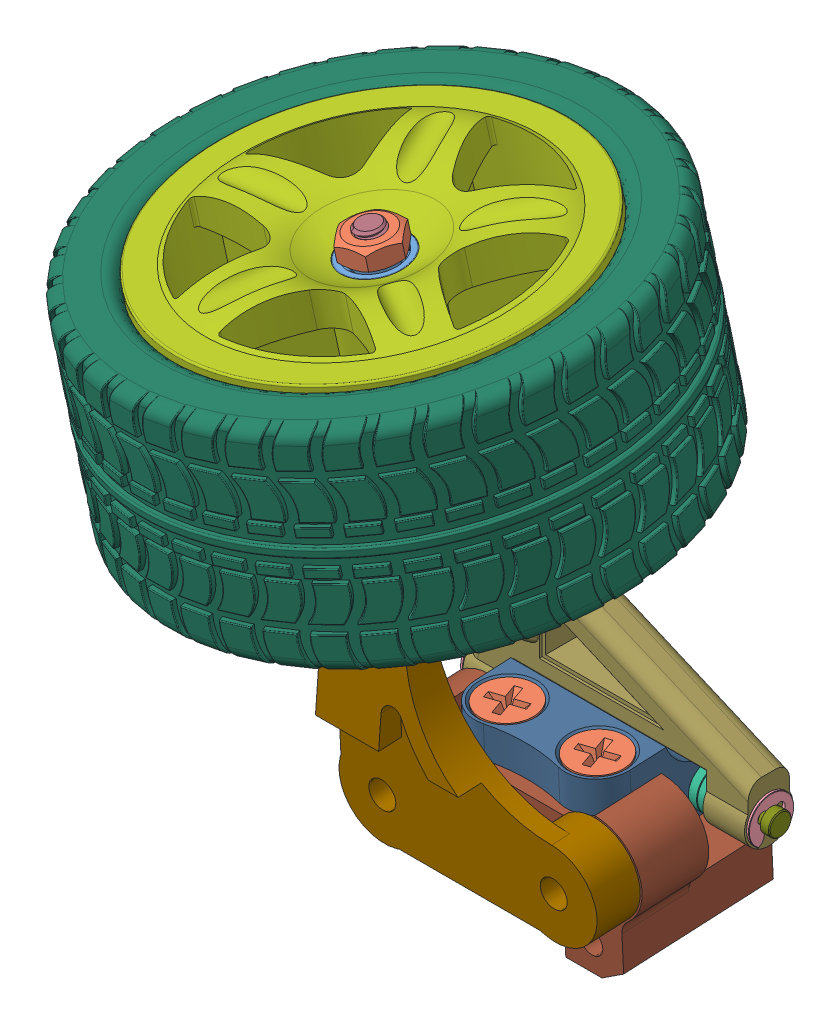
SolidWorks assembly 右前轮, configuration 默认. Lengths in mm.
35 component instances, 21 part files, 72 mates.
Components (placement in the parent):
- 半球型活动头-1: 半球型活动头 [默认] at (-78.9376 -3.6559 -21.7438) x (0.882357 -0.468353 -0.045739) z (-0.470427 -0.875403 -0.111216) size (5.8 4.8 5.8)
- 沉头螺钉-M3-1: 沉头螺钉-M3 [GB_WOOD_SCREWS_TYPE135 3X8-C] at (-71.5787 -28.9343 -13.2981) x (0 -0.998761 -0.049759) z (0.300279 -0.047463 0.95267) size (8.5 6 6)
- 弹簧-1: 弹簧 [默认] at (-76.6558 -7.7661 0.9567) x (0.999717 0.018907 0.014412) z (-0.012048 -0.119649 0.992743) size (4.64 4.5 4.5)
- 挡圈-M2.5-1: 挡圈-M2.5 [默认] at (-50.8787 -34.3142 -21.8764) x (0 0 1) z (-1 0 0) size (5 4.5 0.3)
- 挡圈-M3-1: 挡圈-M3 [默认] at (-76.3474 -4.7031 -24.4576) x (0.999921 0.00221 0.012402) z (-0.012048 -0.119649 0.992743) size (6 5.32 0.3)
- 垫片-M3-1: 垫片-M3 [默认] at (-56.8787 -34.3142 -21.8764) x (0 0.117541 -0.993068) z (-1 0 0) size (4.5 4.5 1)
- 轮毂-前轮-1: 轮毂-前轮 [默认] at (-82.7922 12.0911 -9.4167) x (-0.642369 0.012117 -0.7663) z (-0.756725 -0.168364 0.631681) size (40 26.36 40)
- 前拉杆球头-1: 前拉杆球头 [默认] at (-76.3787 -5.0142 -21.8764) x (0 1 0) z (1 0 0) size (16.5 5.82 9)
- 前轮悬挂固定座-右-1: 前轮悬挂固定座-右 [默认] at (-76.5787 -35.9843 -6.4404) x (1 0 0) z (0 -0.049759 0.998761) size (28.6 39.6 7.36)
- 前轮悬挂连接件上半部分-右-1: 前轮悬挂连接件上半部分-右 [默认] at (-57.9787 -34.3142 -21.8764) x (0 -0.049759 0.998761) z (-1 0 0) size (14.6 8.6 17.2)
- 前轮悬挂连接件下半部分-右-1: 前轮悬挂连接件下半部分-右 [默认] at (-57.5787 -35.845 -9.237) x (0 -0.998761 -0.049759) z (0 0.049759 -0.998761) size (16 29 16.6)
- 前轮悬挂支撑臂-1: 前轮悬挂支撑臂 [默认] at (-76.3787 -34.3142 -24.1764) size (31.32 16.5 6)
- 前轮轴-1: 前轮轴 [默认] at (-80.2678 -8.4104 -11.8569) x (0.428571 0.158643 -0.889471) z (0.121363 -0.98565 -0.117322) size (4.6 4.19 25.74)
- 丝杆-1: 丝杆 [默认] at (-76.3787 -23.5142 -21.8764) x (0.776614 0 -0.629977) z (0 -1 0) size (3.03 3.46 12.09)
- 橡胶胎-1: 橡胶胎 [默认] at (-82.8165 12.2883 -9.3932) x (-0.642369 0.012117 -0.7663) z (-0.756725 -0.168364 0.631681) size (52.2 24.12 52.2)
- 悬挂销钉-M2.5-1: 悬挂销钉-M2.5 [默认] at (-49.8787 -34.3142 -21.8764) x (0 0.773962 0.633232) z (-1 0 0) size (2.5 2.5 34)
- 悬挂销钉-M3-1: 悬挂销钉-M3 [默认] at (-76.3378 -4.6074 -25.2518) x (0.999717 0.018907 0.014412) z (-0.012048 -0.119649 0.992743) size (3 3 27.5)
- 沉头螺钉-M3-2: 沉头螺钉-M3 [GB_WOOD_SCREWS_TYPE135 3X8-C] at (-61.5787 -28.9343 -13.2981) x (0 -0.998761 -0.049759) z (0.300279 -0.047463 0.95267) size (8.5 6 6)
- 垫片-M3-2: 垫片-M3 [默认] at (-55.8787 -34.3142 -21.8764) x (0 0 1) z (-1 0 0) size (4.5 4.5 1)
- 垫片-M3-3: 垫片-M3 [默认] at (-77.1787 -34.3142 -21.8764) x (0 0 -1) z (1 0 0) size (4.5 4.5 1)
- 垫片-M3-4: 垫片-M3 [默认] at (-76.1787 -34.3142 -21.8764) x (0 0 -1) z (1 0 0) size (4.5 4.5 1)
- 挡圈-M2.5-2: 挡圈-M2.5 [默认] at (-82.8787 -34.3142 -21.8764) x (0 0 -1) z (1 0 0) size (5 4.5 0.3)
- 挡圈-M3-2: 挡圈-M3 [默认] at (-76.6558 -7.7661 0.9567) x (0.999717 0.018907 0.014412) z (-0.012048 -0.119649 0.992743) size (6 5.32 0.3)
- 半球型活动头-2: 半球型活动头 [默认] at (-78.9157 -8.7015 -5.6303) x (0.805874 0.586592 0.080479) z (-0.591964 0.800996 0.089355) size (5.8 4.8 5.8)
- 转向摇臂-右-1: 转向摇臂-右 [默认] at (-76.5378 -6.5935 -8.7722) x (-0.121363 0.98565 0.117322) z (0.012048 0.119649 -0.992743) size (14.2 22.2 10)
- 垫片-M3-5: 垫片-M3 [默认] at (-76.4076 -5.3013 -19.4939) x (0.999911 0.004269 0.01265) z (-0.012048 -0.119649 0.992743) size (4.5 4.5 1)
- 垫片-M3-6: 垫片-M3 [默认] at (-76.5378 -6.5935 -8.7722) x (0.999924 0.001254 0.012287) z (-0.012048 -0.119649 0.992743) size (4.5 4.5 1)
- 深沟轴承-M7-1: 深沟轴承-M7 [Rolling bearings 618-3 GB 276-94] at (-81.4815 1.4461 -10.6837) x (0.121363 -0.98565 -0.117322) z (-0.959278 -0.146837 0.241296) size (2 7 7)
- 深沟轴承-M7-2: 深沟轴承-M7 [Rolling bearings 618-3 GB 276-94] at (-82.4524 9.3313 -9.7452) x (-0.121363 0.98565 0.117322) z (-0.756725 -0.168364 0.631681) size (2 7 7)
- 挡圈-M3-3: 挡圈-M3 [默认] at (-79.9159 -11.2688 -12.1972) x (0.98348 0.135396 -0.120141) z (-0.121363 0.98565 0.117322) size (6 5.32 0.3)
- 六角螺母-M3-1: 六角螺母-M3 [GB_FASTENER_NUT_SNAB1 M3-C] at (-82.865 12.6825 -9.3463) x (0.98348 0.135396 -0.120141) z (-0.121363 0.98565 0.117322) size (6.35 5.5 2.4)
- 半球型活动头-3: 半球型活动头 [默认] at (-93.5938 -11.5359 -14.8129) x (0.999913 -0.006745 0.011322) z (0.005341 0.992793 0.11972) size (5.8 4.8 5.8)
- 六角螺母-M3-2: 六角螺母-M3 [GB_FASTENER_NUT_SNAB1 M3-C] at (-90.6651 -11.2683 -17.1627) x (0.999927 -0.001083 0.012005) z (-0.012048 -0.119649 0.992743) size (6.35 5.5 2.4)
- 前拉杆球头-2: 前拉杆球头 [默认] at (-90.694 -11.5554 -14.7801) x (-0.064566 0.99194 0.109027) z (-0.997913 -0.064164 -0.007192) size (16.5 5.82 9)
- 十字半圆头长螺钉-M3-1: 十字半圆头长螺钉-M3 [GB_WOOD_SCREWS_TYPE136 M3X8-N] at (-90.7852 -12.4612 -7.265) x (0.012048 0.119649 -0.992743) z (0.99274 0.117391 0.026197) size (12.81 5.8 5.8)
Mates (geometry in assembly coordinates):
- 同心2: concentric anti-aligned: cylinder of 前轮悬挂连接件上半部分-右-1 through (-75.1787 -34.3142 -21.8764) axis (1 0 0) radius 1.25; cylinder of 前轮悬挂支撑臂-1 through (-51.1787 -34.3142 -21.8764) axis (-1 0 0) radius 1.25
- 重合1: coincident anti-aligned: plane of 前轮悬挂连接件上半部分-右-1 through (-75.1787 -32.2807 -16.4686) normal (0 -0.998761 -0.049759); plane of 前轮悬挂连接件下半部分-右-1 through (-76.5787 -32.2807 -16.4686) normal (0 0.998761 0.049759)
- 重合2: coincident anti-aligned: plane of 前轮悬挂连接件上半部分-右-1 through (-75.1787 -37.2745 -16.7174) normal (0 -0.049759 0.998761); plane of 前轮悬挂连接件下半部分-右-1 through (-76.5787 -35.4768 -16.6278) normal (0 0.049759 -0.998761)
- 同心7: concentric aligned: cylinder of 前轮悬挂连接件上半部分-右-1 through (-61.5787 -28.8345 -13.2931) axis (0 0.998761 0.049759) radius 1.7; cylinder of 前轮悬挂连接件下半部分-右-1 through (-61.5787 -32.43 -13.4723) axis (0 0.998761 0.049759) radius 1.25
- 重合3: coincident aligned: cone of 沉头螺钉-M3-1 through (-71.5787 -30.6322 -13.3827) axis (0 -0.998761 -0.049759); cone of 前轮悬挂连接件上半部分-右-1 through (-71.5787 -28.8345 -13.2931) axis (0 -0.998761 -0.049759)
- 重合4: coincident aligned: cone of 前轮悬挂连接件上半部分-右-1 through (-61.5787 -28.8345 -13.2931) axis (0 -0.998761 -0.049759); cone of 沉头螺钉-M3-2 through (-61.5787 -30.6322 -13.3827) axis (0 -0.998761 -0.049759)
- 同心8: concentric anti-aligned: cylinder of 前拉杆球头-1 through (-76.3787 -17.0142 -21.8764) axis (0 -1 0) radius 1.25; cylinder of 前轮悬挂支撑臂-1 through (-76.3787 -20.5142 -21.8764) axis (0 1 0) radius 1.25
- 平行3: parallel aligned: plane of 前拉杆球头-1 through (-80.3043 -0.5142 -24.0764) normal (0 0 -1); plane of 前轮悬挂支撑臂-1 through (-76.3787 -34.3142 -24.1764) normal (0 0 -1)
- 距离1: distance = 3.5 mm anti-aligned: plane of 前轮悬挂支撑臂-1 through (-79.3787 -20.5142 -19.5764) normal (0 1 0); plane of 前拉杆球头-1 through (-76.3787 -17.0142 -21.8764) normal (0 -1 0)
- 同心9: concentric: sphere of 半球型活动头-1; sphere of 前拉杆球头-1
- 重合7: coincident anti-aligned: plane of 前轮悬挂固定座-右-1 through (-76.5787 -35.845 -9.237) normal (0 0.049759 -0.998761); plane of 前轮悬挂连接件下半部分-右-1 through (-76.5787 -35.845 -9.237) normal (0 -0.049759 0.998761)
- 同心10: concentric aligned: cylinder of 前轮悬挂固定座-右-1 through (-57.5787 -36.0838 -4.4429) axis (0 0.049759 -0.998761) radius 1.5; cylinder of 前轮悬挂连接件下半部分-右-1 through (-57.5787 -35.4768 -16.6278) axis (0 0.049759 -0.998761) radius 1.25
- 同心11: concentric aligned: cylinder of 前轮悬挂固定座-右-1 through (-76.5787 -36.0838 -4.4429) axis (0 0.049759 -0.998761) radius 1.5; cylinder of 前轮悬挂连接件下半部分-右-1 through (-76.5787 -35.4768 -16.6278) axis (0 0.049759 -0.998761) radius 1.25
- 重合8: coincident anti-aligned: plane of 垫片-M3-1 through (-56.7787 -34.3142 -21.8764) normal (1 0 0); plane of 垫片-M3-2 through (-56.7787 -34.3142 -21.8764) normal (-1 0 0)
- 同心12: concentric aligned: cylinder of 垫片-M3-1 through (-57.7787 -34.3142 -21.8764) axis (1 0 0) radius 1.5; cylinder of 垫片-M3-2 through (-56.7787 -34.3142 -21.8764) axis (1 0 0) radius 1.5
- 重合9: coincident anti-aligned: plane of 垫片-M3-3 through (-76.1787 -34.3142 -21.8764) normal (1 0 0); plane of 垫片-M3-4 through (-76.1787 -34.3142 -21.8764) normal (-1 0 0)
- 同心13: concentric aligned: cylinder of 垫片-M3-3 through (-76.1787 -34.3142 -21.8764) axis (-1 0 0) radius 1.5; cylinder of 垫片-M3-4 through (-75.1787 -34.3142 -21.8764) axis (-1 0 0) radius 1.5
- 同心14: concentric anti-aligned: cylinder of 前轮悬挂支撑臂-1 through (-51.1787 -34.3142 -21.8764) axis (-1 0 0) radius 1.25; cylinder of 悬挂销钉-M2.5-1 through (-83.8787 -34.3142 -21.8764) axis (1 0 0) radius 1.25
- 同心15: concentric aligned: cylinder of 垫片-M3-1 through (-57.7787 -34.3142 -21.8764) axis (1 0 0) radius 1.5; cylinder of 悬挂销钉-M2.5-1 through (-83.8787 -34.3142 -21.8764) axis (1 0 0) radius 1.25
- 重合11: coincident anti-aligned: plane of 前轮悬挂支撑臂-1 through (-77.1787 -37.0142 -19.5764) normal (1 0 0); plane of 垫片-M3-3 through (-77.1787 -34.3142 -21.8764) normal (-1 0 0)
- 同心16: concentric anti-aligned: cylinder of 悬挂销钉-M2.5-1 through (-83.8787 -34.3142 -21.8764) axis (1 0 0) radius 1.25; cylinder of 垫片-M3-3 through (-76.1787 -34.3142 -21.8764) axis (-1 0 0) radius 1.5
- 重合13: coincident anti-aligned: plane of 挡圈-M2.5-1 through (-50.8787 -34.0101 -22.3348) normal (1 0 0); plane of 悬挂销钉-M2.5-1 through (-50.8787 -34.3142 -21.8764) normal (-1 0 0)
- 同心17: concentric aligned: cylinder of 挡圈-M2.5-1 through (-51.1787 -34.3142 -21.8764) axis (1 0 0) radius 1.1; cylinder of 悬挂销钉-M2.5-1 through (-51.2787 -34.3142 -21.8764) axis (1 0 0) radius 1.1
- 重合14: coincident anti-aligned: plane of 挡圈-M2.5-1 through (-51.1787 -34.0101 -22.3348) normal (-1 0 0); plane of 前轮悬挂支撑臂-1 through (-51.1787 -30.0142 -19.5764) normal (1 0 0)
- 重合15: coincident anti-aligned: plane of 悬挂销钉-M2.5-1 through (-82.8787 -34.3142 -21.8764) normal (1 0 0); plane of 挡圈-M2.5-2 through (-82.8787 -34.0101 -21.4181) normal (-1 0 0)
- 同心18: concentric aligned: cylinder of 悬挂销钉-M2.5-1 through (-82.5787 -34.3142 -21.8764) axis (-1 0 0) radius 1.1; cylinder of 挡圈-M2.5-2 through (-82.5787 -34.3142 -21.8764) axis (-1 0 0) radius 1.1
- 同心19: concentric: sphere of 前轮悬挂固定座-右-1; sphere of 半球型活动头-2
- 重合16: coincident anti-aligned: plane of 悬挂销钉-M3-1 through (-76.6594 -7.802 1.2545) normal (0.012048 0.119649 -0.992743); plane of 挡圈-M3-2 through (-77.2083 -7.4556 1.2896) normal (-0.012048 -0.119649 0.992743)
- 同心20: concentric anti-aligned: cylinder of 悬挂销钉-M3-1 through (-76.6558 -7.7661 0.9567) axis (-0.012048 -0.119649 0.992743) radius 1.25; cylinder of 挡圈-M3-2 through (-76.6594 -7.802 1.2545) axis (0.012048 0.119649 -0.992743) radius 1.3
- 重合17: coincident anti-aligned: plane of 弹簧-1 through (-78.7178 -10.0394 0.6576) normal (-0.012048 -0.119649 0.992743); plane of 挡圈-M3-2 through (-77.2047 -7.4197 0.9917) normal (0.012048 0.119649 -0.992743)
- 重合18: coincident aligned: plane of 弹簧-1; plane of 悬挂销钉-M3-1
- 重合19: coincident aligned: plane of 弹簧-1; plane of 悬挂销钉-M3-1
- 重合20: coincident anti-aligned: plane of 弹簧-1 through (-74.4983 2.6826 -1.7871) normal (0.012048 0.119649 -0.992743); plane of 半球型活动头-2 through (-74.9597 -12.2474 -3.5921) normal (-0.012048 -0.119649 0.992743)
- 同心21: concentric aligned: cylinder of 悬挂销钉-M3-1 through (-76.6691 -7.8977 2.0487) axis (0.012048 0.119649 -0.992743) radius 1.5; cylinder of 半球型活动头-2 through (-76.6076 -7.2875 -3.0143) axis (0.012048 0.119649 -0.992743) radius 1.5
- 同心22: concentric anti-aligned: cylinder of 半球型活动头-1 through (-76.3498 -4.727 -24.259) axis (-0.012048 -0.119649 0.992743) radius 1.5; cylinder of 悬挂销钉-M3-1 through (-76.6691 -7.8977 2.0487) axis (0.012048 0.119649 -0.992743) radius 1.5
- 同心23: concentric anti-aligned: cylinder of 悬挂销钉-M3-1 through (-76.6691 -7.8977 2.0487) axis (0.012048 0.119649 -0.992743) radius 1.5; cylinder of 转向摇臂-右-1 through (-76.504 -6.2585 -11.5519) axis (-0.012048 -0.119649 0.992743) radius 1.5
- 重合21: coincident anti-aligned: plane of 转向摇臂-右-1 through (-76.4197 -5.421 -18.5011) normal (0.012048 0.119649 -0.992743); plane of 垫片-M3-5 through (-76.4197 -5.421 -18.5011) normal (-0.012048 -0.119649 0.992743)
- 同心24: concentric aligned: cylinder of 悬挂销钉-M3-1 through (-76.6691 -7.8977 2.0487) axis (0.012048 0.119649 -0.992743) radius 1.5; cylinder of 垫片-M3-5 through (-76.4197 -5.421 -18.5011) axis (0.012048 0.119649 -0.992743) radius 1.5
- 重合22: coincident anti-aligned: plane of 半球型活动头-1 through (-75.4919 -0.1619 -18.8633) normal (-0.012048 -0.119649 0.992743); plane of 垫片-M3-5 through (-76.4076 -5.3013 -19.4939) normal (0.012048 0.119649 -0.992743)
- 同心25: concentric aligned: cylinder of 悬挂销钉-M3-1 through (-76.6691 -7.8977 2.0487) axis (0.012048 0.119649 -0.992743) radius 1.5; cylinder of 垫片-M3-6 through (-76.5498 -6.7132 -7.7795) axis (0.012048 0.119649 -0.992743) radius 1.5
- 重合24: coincident anti-aligned: plane of 转向摇臂-右-1 through (-76.5378 -6.5935 -8.7722) normal (-0.012048 -0.119649 0.992743); plane of 垫片-M3-6 through (-76.5378 -6.5935 -8.7722) normal (0.012048 0.119649 -0.992743)
- 重合25: coincident anti-aligned: plane of 半球型活动头-2 through (-74.9018 -11.6731 -8.3573) normal (0.012048 0.119649 -0.992743); plane of 垫片-M3-6 through (-76.5498 -6.7132 -7.7795) normal (-0.012048 -0.119649 0.992743)
- 重合26: coincident anti-aligned: plane of 挡圈-M3-1 through (-76.8903 -4.3476 -24.4213) normal (0.012048 0.119649 -0.992743); circle of 悬挂销钉-M3-1
- 同心26: concentric aligned: cylinder of 挡圈-M3-1 through (-76.351 -4.739 -24.1597) axis (0.012048 0.119649 -0.992743) radius 1.3; cylinder of 悬挂销钉-M3-1 through (-76.3522 -4.7509 -24.0605) axis (0.012048 0.119649 -0.992743) radius 1.25
- 同心27: concentric anti-aligned: cylinder of 前轮悬挂支撑臂-1 through (-76.3787 -20.5142 -21.8764) axis (0 1 0) radius 1.25; cylinder of 丝杆-1 through (-76.3787 -11.5142 -21.8764) axis (0 -1 0) radius 1.5
- 距离3: distance = 3 mm anti-aligned: plane of 丝杆-1 through (-76.3787 -23.5142 -21.8764) normal (0 -1 0); plane of 前轮悬挂支撑臂-1 through (-79.3787 -20.5142 -19.5764) normal (0 1 0)
- 同心28: concentric aligned: cylinder of 前轮轴-1 through (-82.9378 13.2739 -9.2759) axis (0.121363 -0.98565 -0.117322) radius 1.5; cylinder of 转向摇臂-右-1 through (-81.1174 -1.5108 -11.0357) axis (0.121363 -0.98565 -0.117322) radius 1.5
- 重合28: coincident anti-aligned: plane of 前轮轴-1 through (-82.5303 0.0837 -8.846) normal (-0.012048 -0.119649 0.992743); plane of 转向摇臂-右-1 through (-81.438 -8.7872 -9.9019) normal (0.012048 0.119649 -0.992743)
- 重合29: coincident: moEndPointRef_w of 前轮轴-1; plane of 转向摇臂-右-1 through (-76.3314 -8.2691 -8.9717) normal (-0.121363 0.98565 0.117322)
- 重合30: coincident anti-aligned: plane of 前轮轴-1 through (-79.9159 -11.2688 -12.1972) normal (-0.121363 0.98565 0.117322); plane of 挡圈-M3-3 through (-80.4969 -11.3059 -12.4863) normal (0.121363 -0.98565 -0.117322)
- 同心29: concentric anti-aligned: cylinder of 前轮轴-1 through (-79.9159 -11.2688 -12.1972) axis (-0.121363 0.98565 0.117322) radius 1.3; cylinder of 挡圈-M3-3 through (-79.9523 -10.9731 -12.162) axis (0.121363 -0.98565 -0.117322) radius 1.3
- 同心30: concentric anti-aligned: cylinder of 轮毂-前轮-1 through (-81.6028 2.4318 -10.5664) axis (0.121363 -0.98565 -0.117322) radius 3.5; cylinder of 深沟轴承-M7-1 through (-82.5386 10.0318 -9.6618) axis (-0.121363 0.98565 0.117322) radius 3.5
- 重合31: coincident anti-aligned: plane of 轮毂-前轮-1 through (-81.6028 2.4318 -10.5664) normal (0.121363 -0.98565 -0.117322); plane of 深沟轴承-M7-1 through (-80.7101 2.1404 -7.1947) normal (-0.121363 0.98565 0.117322)
- 同心31: concentric anti-aligned: cylinder of 轮毂-前轮-1 through (-82.331 8.3457 -9.8625) axis (-0.121363 0.98565 0.117322) radius 3.5; cylinder of 深沟轴承-M7-2 through (-81.3952 0.7456 -10.7671) axis (0.121363 -0.98565 -0.117322) radius 3.5
- 重合32: coincident anti-aligned: plane of 轮毂-前轮-1 through (-82.331 8.3457 -9.8625) normal (-0.121363 0.98565 0.117322); plane of 深沟轴承-M7-2 through (-84.5793 8.3881 -12.5445) normal (0.121363 -0.98565 -0.117322)
- 同心32: concentric aligned: cylinder of 轮毂-前轮-1 through (-82.7922 12.0911 -9.4167) axis (-0.121363 0.98565 0.117322) radius 18; cylinder of 橡胶胎-1 through (-82.7922 12.0911 -9.4167) axis (-0.121363 0.98565 0.117322) radius 20
- 重合33: coincident aligned: plane of 轮毂-前轮-1 through (-70.0733 11.8512 5.7561) normal (-0.121363 0.98565 0.117322); plane of 橡胶胎-1 through (-66.4118 11.7821 10.124) normal (-0.121363 0.98565 0.117322)
- 同心33: concentric anti-aligned: cylinder of 前轮轴-1 through (-82.9378 13.2739 -9.2759) axis (0.121363 -0.98565 -0.117322) radius 1.5; cylinder of 深沟轴承-M7-1 through (-82.3275 8.3175 -9.8658) axis (-0.121363 0.98565 0.117322) radius 1.5
- 重合34: coincident anti-aligned: plane of 前轮轴-1 through (-81.3601 0.4605 -10.801) normal (-0.121363 0.98565 0.117322); plane of 深沟轴承-M7-1 through (-80.9775 0.3356 -9.356) normal (0.121363 -0.98565 -0.117322)
- 同心34: concentric anti-aligned: cylinder of 前轮轴-1 through (-82.9378 13.2739 -9.2759) axis (0.121363 -0.98565 -0.117322) radius 1.5; cylinder of 六角螺母-M3-1 through (-82.5737 10.317 -9.6278) axis (-0.121363 0.98565 0.117322) radius 1.2295
- 重合35: coincident anti-aligned: plane of 深沟轴承-M7-2 through (-83.5373 10.3351 -10.7773) normal (-0.121363 0.98565 0.117322); plane of 六角螺母-M3-1 through (-79.4508 10.7469 -10.0093) normal (0.121363 -0.98565 -0.117322)
- 重合36: coincident aligned: plane of 轮毂-前轮-1; plane of 深沟轴承-M7-2
- 重合37: coincident aligned: plane of 轮毂-前轮-1; plane of 橡胶胎-1
- 同心351: concentric aligned: cylinder of 转向摇臂-右-1 through (-90.7229 -11.8426 -12.3975) axis (-0.012048 -0.119649 0.992743) radius 1.5; cylinder of 十字半圆头长螺钉-M3-1 through (-90.9494 -14.0919 6.2654) axis (-0.012048 -0.119649 0.992743) radius 1.5
- 重合381: coincident anti-aligned: plane of 转向摇臂-右-1 through (-76.5378 -6.5935 -8.7722) normal (-0.012048 -0.119649 0.992743); plane of 十字半圆头长螺钉-M3-1 through (-92.2458 -12.3537 -9.6571) normal (0.012048 0.119649 -0.992743)
- 重合39: coincident anti-aligned: plane of 转向摇臂-右-1 through (-76.504 -6.2585 -11.5519) normal (0.012048 0.119649 -0.992743); plane of 半球型活动头-3 through (-92.3774 -16.7956 -13.0145) normal (-0.012048 -0.119649 0.992743)
- 同心36: concentric anti-aligned: cylinder of 半球型活动头-3 through (-90.7229 -11.8426 -12.3975) axis (0.012048 0.119649 -0.992743) radius 1.5; cylinder of 十字半圆头长螺钉-M3-1 through (-90.9494 -14.0919 6.2654) axis (-0.012048 -0.119649 0.992743) radius 1.5
- 重合40: coincident anti-aligned: plane of 半球型活动头-3 through (-92.3196 -16.2213 -17.7797) normal (0.012048 0.119649 -0.992743); plane of 六角螺母-M3-2 through (-87.4899 -11.2717 -17.1245) normal (-0.012048 -0.119649 0.992743)
- 同心37: concentric anti-aligned: cylinder of 六角螺母-M3-2 through (-90.6362 -10.9811 -19.5452) axis (-0.012048 -0.119649 0.992743) radius 1.2295; cone of 十字半圆头长螺钉-M3-1 through (-90.6603 -11.2204 -17.5597) axis (0.012048 0.119649 -0.992743)
- 同心38: concentric: sphere of 半球型活动头-3; sphere of 前拉杆球头-2
- 重合382: coincident anti-aligned: plane of 前轮悬挂连接件上半部分-右-1 through (-75.1787 -34.3142 -21.8764) normal (-1 0 0); plane of 垫片-M3-4 through (-75.1787 -34.3142 -21.8764) normal (1 0 0)
- 距离4: distance = 0.1 mm anti-aligned: plane of 前轮悬挂连接件上半部分-右-1 through (-57.9787 -34.3142 -21.8764) normal (1 0 0); plane of 垫片-M3-1 through (-57.8787 -34.3142 -21.8764) normal (-1 0 0)
